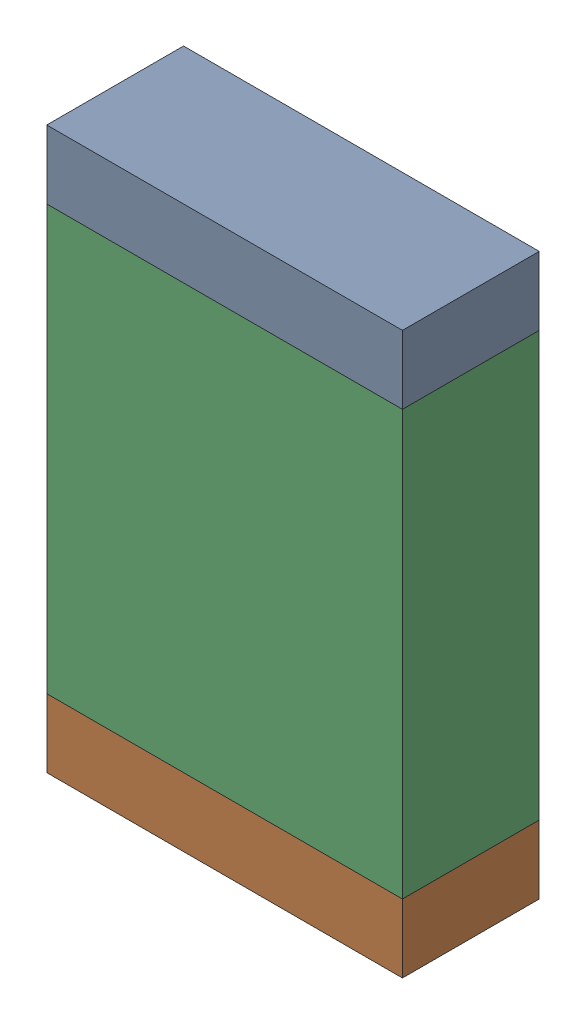
SolidWorks assembly C98, configuration Default. Lengths in mm.
Overall size (1.3 2.05 0.5).
6 component instances, 2 part files, 0 mates.
Components (placement in the parent):
- 836753264-1: 836753264 [Default] at (111.85 71.375 0) size (1.3 0.25 0.5)
  - Extruded_22-1: Extruded_22 [Default] at origin size (1.3 0.25 0.5)
- 836753264-2: 836753264 [Default] at (111.85 69.575 0) size (1.3 0.25 0.5)
  - Extruded_22-1: Extruded_22 [Default] at origin size (1.3 0.25 0.5)
- 836753008-1: 836753008 [Default] at (111.85 70.475 0) size (1.3 1.55 0.5)
  - Extruded_23-1: Extruded_23 [Default] at origin size (1.3 1.55 0.5)
